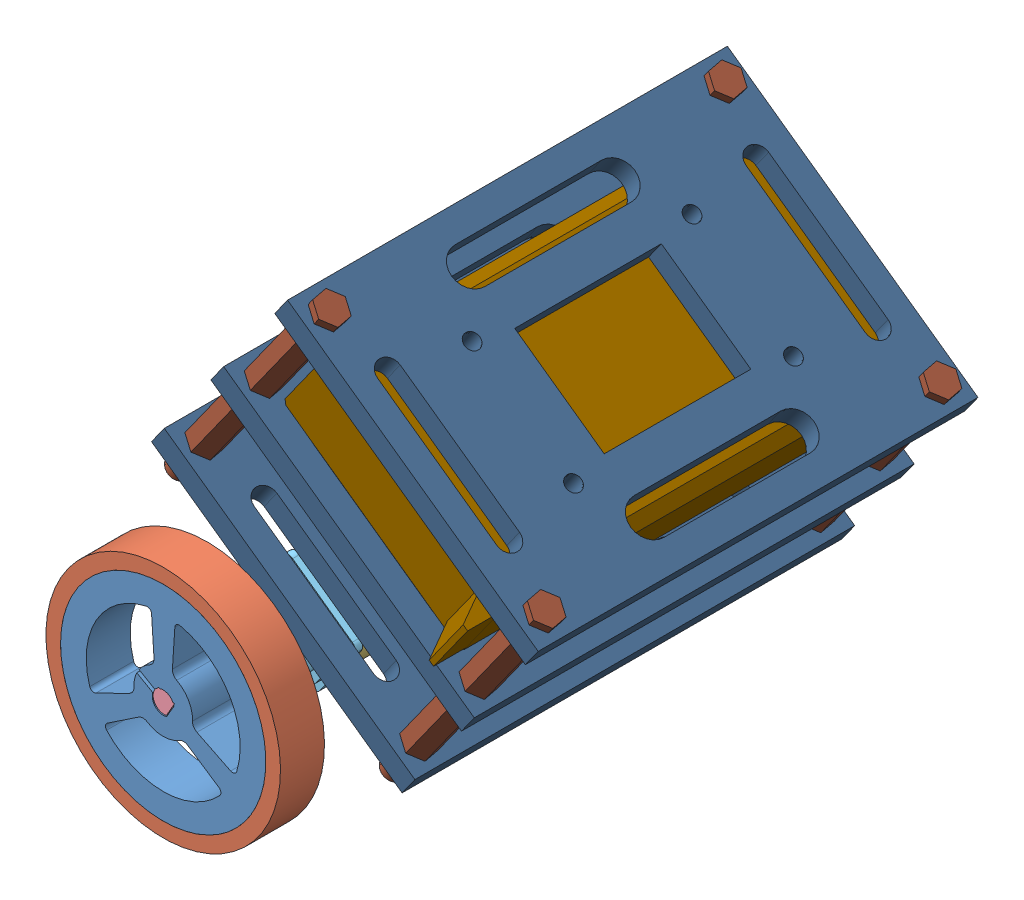
SolidWorks assembly 轮胎整体, configuration 默认. Lengths in mm.
Overall size (61.28 66.46 85.4).
38 component instances, 11 part files, 27 mates.
Components (placement in the parent):
- 轮胎-1: 轮胎 [默认] at (-1.9832 -0.6429 25) size (28 28 6)
- 轮胎外胎-1: 轮胎外胎 [默认] at (-1.9832 -0.6429 25) x (0.781162 0.624329 0) z (0 0 1) size (32 32 6)
- n20 motor-2: n20 motor [轴长10mm] at (-1.7647 -0.4925 7.8886) x (0 0 -1) z (0.581035 0.813878 0) size (36.2 12.14 10.87)
  - motor-1: motor [默认] at (-3.4114 0.0905 -5.0483) size (19.5 12 10)
  - n20_shaft-1: n20_shaft [10mm] at (-13.1114 0.0905 -0.0483) x (0 -0.096252 -0.995357) z (0 0.995357 -0.096252) size (3 12 3)
  - n20_gearbox-1: n20_gearbox [默认] at (-11.4114 0.0905 -0.0483) x (0 1 0) z (-1 0 0) size (12 10 9.7)
  - cross recessed countersunk head screws gb1-1: cross recessed countersunk head screws gb1 [GB_CROSS_SCREWS_TYPE4 M1.6X3-2  H type-N] at (-12.4614 -3.4095 2.4517) size (3 2.7 2.7)
  - cross recessed countersunk head screws gb1-2: cross recessed countersunk head screws gb1 [GB_CROSS_SCREWS_TYPE4 M1.6X3-2  H type-N] at (-12.4614 3.5905 -2.5483) x (1 0 0) z (0 0.116872 0.993147) size (3 2.7 2.7)
  - spur gear_gb-1: spur gear_gb [GB - Spur gear 0.25M 10T 20PA 2FW ---S10A75H50L1.0N] at (-8.4114 -2.9095 -2.5483) x (1 0 0) z (0 -0.845955 0.533254) size (2 2.87 3)
  - spur gear_gb-2: spur gear_gb [GB - Spur gear 0.25M 10T 20PA 2FW ---S10A75H50L1.0N] at (-4.4114 0.0905 -0.0483) x (-1 0 0) z (0 0.404067 -0.914729) size (2 2.87 3)
  - spur gear_gb-4: spur gear_gb [GB - Spur gear 0.25M 16T 20PA 2FW ---S16A75H50L1.0N] at (-6.4114 -2.9095 -2.5483) x (1 0 0) z (0 -0.712706 0.701463) size (2 4.44 4.44)
  - spur gear_gb-6: spur gear_gb [GB - Spur gear 0.25M 19T 20PA 2FW ---S19A75H50L1.0N] at (-9.9114 0.0905 -0.0483) x (1 0 0) z (0 0.321468 -0.94692) size (2 5.22 5.24)
  - spur gear_gb-8: spur gear_gb [GB - Spur gear 0.25M 11T 20PA 3FW ---S11A75H50L1.0N] at (-10.9114 3.0905 2.9517) x (1 0 0) z (0 -0.604063 0.796937) size (3 3.2 3.23)
  - spur gear_gb-10: spur gear_gb [GB - Spur gear 0.25M 19T 20PA 1FW ---S19A75H50L1.0N] at (-11.4114 0.0905 -0.0483) x (1 0 0) z (0 -0.330889 0.94367) size (1 5.22 5.24)
- 零件5-1: 零件5 [默认] at (-1.9832 -0.6429 -3.7) x (0.813878 -0.581035 0) z (0 0 -1) size (11.6 18.42 6)
- 轮胎-2: 轮胎 [默认] at (-1.9832 -0.6429 -54.4) size (28 28 6)
- 轮胎外胎-2: 轮胎外胎 [默认] at (-1.9832 -0.6429 -54.4) x (0.781162 0.624329 0) z (0 0 1) size (32 32 6)
- n20 motor-3: n20 motor [轴长10mm] at (-2.0543 -0.8981 -31.2886) x (0 0 1) z (-0.581035 -0.813878 0) size (36.2 12.14 10.87)
  - motor-1: motor [默认] at (-3.4114 0.0905 -5.0483) size (19.5 12 10)
  - n20_shaft-1: n20_shaft [10mm] at (-13.1114 0.0905 -0.0483) x (0 -0.096252 -0.995357) z (0 0.995357 -0.096252) size (3 12 3)
  - n20_gearbox-1: n20_gearbox [默认] at (-11.4114 0.0905 -0.0483) x (0 1 0) z (-1 0 0) size (12 10 9.7)
  - cross recessed countersunk head screws gb1-1: cross recessed countersunk head screws gb1 [GB_CROSS_SCREWS_TYPE4 M1.6X3-2  H type-N] at (-12.4614 -3.4095 2.4517) size (3 2.7 2.7)
  - cross recessed countersunk head screws gb1-2: cross recessed countersunk head screws gb1 [GB_CROSS_SCREWS_TYPE4 M1.6X3-2  H type-N] at (-12.4614 3.5905 -2.5483) x (1 0 0) z (0 0.116872 0.993147) size (3 2.7 2.7)
  - spur gear_gb-1: spur gear_gb [GB - Spur gear 0.25M 10T 20PA 2FW ---S10A75H50L1.0N] at (-8.4114 -2.9095 -2.5483) x (1 0 0) z (0 -0.845955 0.533254) size (2 2.87 3)
  - spur gear_gb-2: spur gear_gb [GB - Spur gear 0.25M 10T 20PA 2FW ---S10A75H50L1.0N] at (-4.4114 0.0905 -0.0483) x (-1 0 0) z (0 0.404067 -0.914729) size (2 2.87 3)
  - spur gear_gb-4: spur gear_gb [GB - Spur gear 0.25M 16T 20PA 2FW ---S16A75H50L1.0N] at (-6.4114 -2.9095 -2.5483) x (1 0 0) z (0 -0.712706 0.701463) size (2 4.44 4.44)
  - spur gear_gb-6: spur gear_gb [GB - Spur gear 0.25M 19T 20PA 2FW ---S19A75H50L1.0N] at (-9.9114 0.0905 -0.0483) x (1 0 0) z (0 0.321468 -0.94692) size (2 5.22 5.24)
  - spur gear_gb-8: spur gear_gb [GB - Spur gear 0.25M 11T 20PA 3FW ---S11A75H50L1.0N] at (-10.9114 3.0905 2.9517) x (1 0 0) z (0 -0.604063 0.796937) size (3 3.2 3.23)
  - spur gear_gb-10: spur gear_gb [GB - Spur gear 0.25M 19T 20PA 1FW ---S19A75H50L1.0N] at (-11.4114 0.0905 -0.0483) x (1 0 0) z (0 -0.330889 0.94367) size (1 5.22 5.24)
- 零件5-2: 零件5 [默认] at (-1.9832 -0.6429 -19.7) x (-0.813878 0.581035 0) z (0 0 1) size (11.6 18.42 6)
- 电池2S-1: 电池2S [默认] at (17.4996 27.9383 -13.4402) x (0 0 -1) z (-0.581035 -0.813878 0) size (62.44 30 12)
- 底板-1: 底板 [默认] at (0.6959 4.3711 -11.8154) x (0 0 -1) z (0.581035 0.813878 0) size (60 42 3)
- 底板-2: 底板 [默认] at (8.798 15.7202 -11.8154) x (0 0 -1) z (0.581035 0.813878 0) size (60 42 3)
- 底板-3: 底板 [默认] at (17.5136 27.9283 -11.8154) x (0 0 -1) z (0.581035 0.813878 0) size (60 42 3)
- 铜柱-1: 铜柱 [默认] at (-12.2108 17.2714 -38.8154) x (0.662398 -0.472892 0.581035) z (-0.581035 -0.813878 0) size (4.05 4.02 36)
- 铜柱-2: 铜柱 [默认] at (-12.2108 17.2714 15.1846) x (0.662398 -0.472892 0.581035) z (-0.581035 -0.813878 0) size (4.05 4.02 36)
- 铜柱-3: 铜柱 [默认] at (17.0888 -3.6459 -38.8154) x (0.662398 -0.472892 0.581035) z (-0.581035 -0.813878 0) size (4.05 4.02 36)
- 铜柱-4: 铜柱 [默认] at (17.0888 -3.6459 15.1846) x (0.662398 -0.472892 0.581035) z (-0.581035 -0.813878 0) size (4.05 4.02 36)
Mates (geometry in assembly coordinates):
- 重合3: coincident aligned: circle of 轮胎-1; circle of 轮胎外胎-1
- 同心1: concentric aligned: circle of n20 motor-2/motor-1; circle of 零件5-1
- 重合5: coincident anti-aligned: plane of n20 motor-2/motor-1 through (5.922 0.1039 -3.7) normal (0 0 -1); plane of 零件5-1 through (-0.9883 -3.1647 -3.7) normal (0 0 1)
- 平行3: parallel anti-aligned: line of n20 motor-2/motor-1 through (-2.3503 6.0096 10.9) axis (0.813878 -0.581035 0); line of 零件5-1 through (7.3489 2.8354 -8.7) axis (-0.813878 0.581035 0)
- 同心2: concentric aligned: circle of 轮胎-1; circle of 零件5-1
- 平行5: parallel anti-aligned: line of 轮胎-1 through (-1.515 -2.068 25) axis (0.5 0.866025 0); line of n20 motor-2/n20_shaft-1 through (-0.4414 -0.011 31) axis (-0.5 -0.866025 0)
- 重合10: coincident aligned: plane of 轮胎-1 through (-1.9832 -0.6429 31) normal (0 0 1); plane of n20 motor-2/n20_shaft-1 through (-1.8664 -0.4793 31) normal (0 0 1)
- 平行6: parallel aligned: plane of 零件5-2 through (10.3525 7.0427 -14.7) normal (0.581035 0.813878 0); plane of 电池2S-1 through (17.4996 27.9383 -13.4402) normal (0.581035 0.813878 0)
- 平行7: parallel aligned: plane of 零件5-2 through (-1.7245 9.313 -14.7) normal (-0.813878 0.581035 0); plane of 电池2S-1 through (-1.681 26.8873 15.5598) normal (-0.813878 0.581035 0)
- 平行8: parallel anti-aligned: plane of 零件5-2 through (10.3525 7.0427 -14.7) normal (0.581035 0.813878 0); plane of 底板-1 through (0.6959 4.3711 -11.8154) normal (-0.581035 -0.813878 0)
- 平行9: parallel aligned: plane of 零件5-2 through (-4.6915 -0.521 -19.7) normal (0 0 -1); plane of 底板-1 through (-14.6525 19.0145 -41.8154) normal (0 0 -1)
- 平行12: parallel anti-aligned: plane of 电池2S-1 through (17.4996 27.9383 -13.4402) normal (0.581035 0.813878 0); plane of 底板-2 through (8.798 15.7202 -11.8154) normal (-0.581035 -0.813878 0)
- 平行13: parallel aligned: plane of 电池2S-1 through (22.7353 9.4563 15.5598) normal (0.813878 -0.581035 0); plane of 底板-2 through (27.6326 5.9601 18.1846) normal (0.813878 -0.581035 0)
- 平行15: parallel anti-aligned: plane of 电池2S-1 through (17.4996 27.9383 -13.4402) normal (0.581035 0.813878 0); plane of 底板-3 through (17.5136 27.9283 -11.8154) normal (-0.581035 -0.813878 0)
- 平行14: parallel aligned: plane of 电池2S-1 through (22.7353 9.4563 -42.4402) normal (0 0 -1); plane of 底板-3 through (2.1652 42.5717 -41.8154) normal (0 0 -1)
- 重合21: coincident anti-aligned: plane of 电池2S-1 through (10.5271 18.1718 -13.4402) normal (-0.581035 -0.813878 0); plane of 底板-2 through (10.5411 18.1618 -11.8154) normal (0.581035 0.813878 0)
- 重合22: coincident anti-aligned: plane of 底板-1 through (2.439 6.8128 -11.8154) normal (0.581035 0.813878 0); plane of 铜柱-1 through (-12.2108 17.2714 -38.8154) normal (-0.581035 -0.813878 0)
- 同心3: concentric anti-aligned: circle of 底板-1; circle of 铜柱-1
- 同心4: concentric anti-aligned: circle of 底板-2; circle of 铜柱-1
- 同心5: concentric anti-aligned: circle of 底板-3; circle of 铜柱-1
- 同心6: concentric anti-aligned: circle of 底板-1; circle of 铜柱-2
- 重合23: coincident anti-aligned: plane of 底板-1 through (2.439 6.8128 -11.8154) normal (0.581035 0.813878 0); plane of 铜柱-2 through (-12.2108 17.2714 15.1846) normal (-0.581035 -0.813878 0)
- 同心7: concentric anti-aligned: circle of 底板-1; circle of 铜柱-3
- 重合25: coincident anti-aligned: plane of 底板-1 through (2.439 6.8128 -11.8154) normal (0.581035 0.813878 0); plane of 铜柱-3 through (17.0888 -3.6459 -38.8154) normal (-0.581035 -0.813878 0)
- 重合26: coincident anti-aligned: plane of 底板-1 through (2.439 6.8128 -11.8154) normal (0.581035 0.813878 0); plane of 铜柱-4 through (17.0888 -3.6459 15.1846) normal (-0.581035 -0.813878 0)
- 同心8: concentric anti-aligned: circle of 底板-1; circle of 铜柱-4
- 重合27: coincident anti-aligned: plane of 电池2S-1 through (17.4996 27.9383 -13.4402) normal (0.581035 0.813878 0); plane of 底板-3 through (17.5136 27.9283 -11.8154) normal (-0.581035 -0.813878 0)
